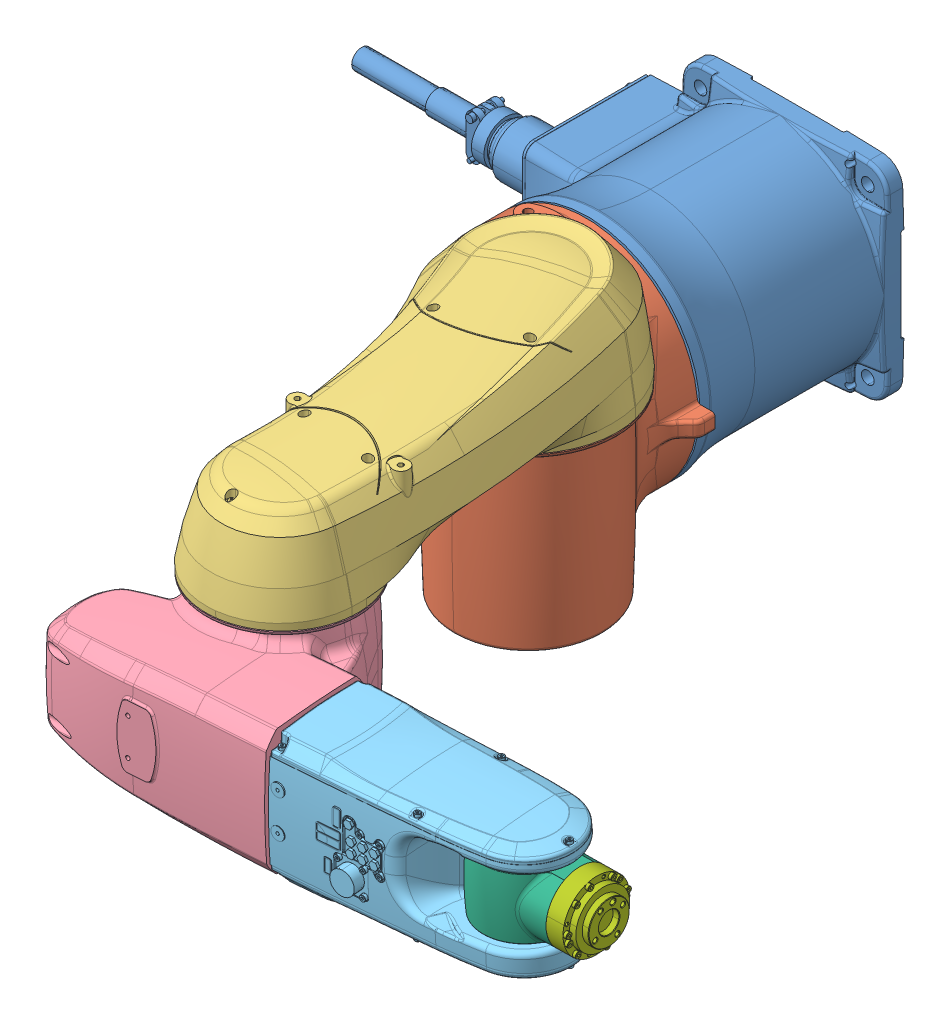
SolidWorks assembly ROBOT, configuration Default. Lengths in mm.
Overall size (820.9 290.39 755.13).
7 component instances, 7 part files, 6 mates.
Components (placement in the parent):
- base-4: base [Default] at origin size (447.67 231.25 211.63)
- link1-1: link1 [Default] at (0 0 185) size (274.13 220.02 235)
- link2-1: link2 [Default] at (75 54.5 335) x (0.992742 0.000004 -0.120264) z (0.120264 -0.000002 0.992742) size (173.33 125.76 428.87)
- link3-1: link3 [Default] at (107.4713 49 603.0403) x (-0.997446 0 0.071427) z (0.071427 0 0.997446) size (223.06 161.04 216.11)
- link4-1: link4 [Default] at (201.675 0 686.5249) x (-0.997446 0 0.071427) z (-0.071427 0.002822 -0.997442) size (254.5 122.01 117.22)
- link5_test1-1: link5_test1 [Default] at (408.1424 -18.9999 671.6859) x (0.999858 -0.000154 -0.016868) z (0.016868 -0.002818 0.999854) size (92.95 64.48 81.91)
- link5_test2-2: link5_test2 [Default] at (459.9389 -0.008 670.8657) x (0.999858 -0.000154 -0.016868) z (0.016407 0.241377 0.970293) size (28 65 65)
Mates (geometry in assembly coordinates):
- Coincident13: coincident anti-aligned: circle of base-4; circle of link1-1
- Coincident14: coincident anti-aligned: circle of link1-1; circle of link2-1
- Coincident15: coincident anti-aligned: circle of link2-1; circle of link3-1
- Coincident16: coincident anti-aligned: circle of link3-1; circle of link4-1
- Coincident17: coincident aligned: circle of link4-1; circle of link5_test1-1
- Coincident18: coincident anti-aligned: circle of link5_test1-1; circle of link5_test2-2
